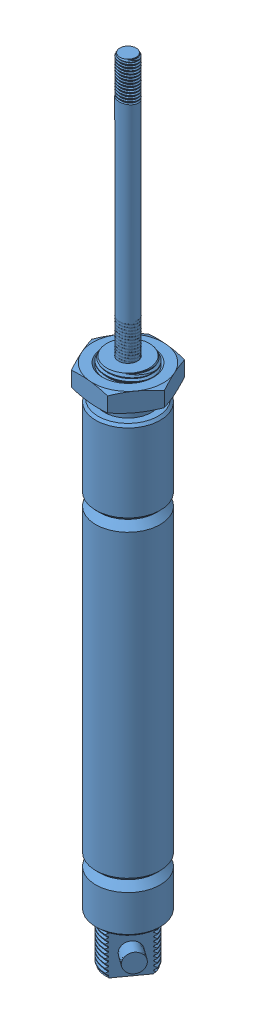
SolidWorks assembly 3in .75 bore piston, configuration Default. Lengths in mm.
Overall size (35.4 267.62 36.23).
2 component instances, 2 part files, 3 mates.
Components (placement in the parent):
- .75 bore Clevis-1: .75 bore Clevis [6498K42] at (-19.5616 -9.187 11.9456) x (0.810757 0 0.585383) z (-0.585383 0 0.810757) size (20.16 35.74 12.7)
- 6498K635-1: 6498K635 [6498K635] at (-19.5616 -98.976 11.9456) x (-0.810757 0 -0.585383) z (0 1 0) size (23.81 27.5 267.62)
Mates (geometry in assembly coordinates):
- Concentric1: concentric aligned: circle of .75 bore Clevis-1; cylinder of 6498K635-1 through (-19.5616 -80.434 11.9456) axis (0 -1 0) radius 3.175
- LimitDistance1: limit distance = 1.524 mm anti-aligned: plane of 6498K635-1 through (-19.5616 -16.045 11.9456) normal (0 1 0); plane of .75 bore Clevis-1 through (-26.996 -14.521 22.2422) normal (0 -1 0)
- Parallel1: parallel aligned: plane of .75 bore Clevis-1 through (-28.4271 -9.187 13.3767) normal (-0.810757 0 -0.585383); plane of 6498K635-1 through (-28.0693 -147.658 15.5931) normal (-0.810757 0 -0.585383)
